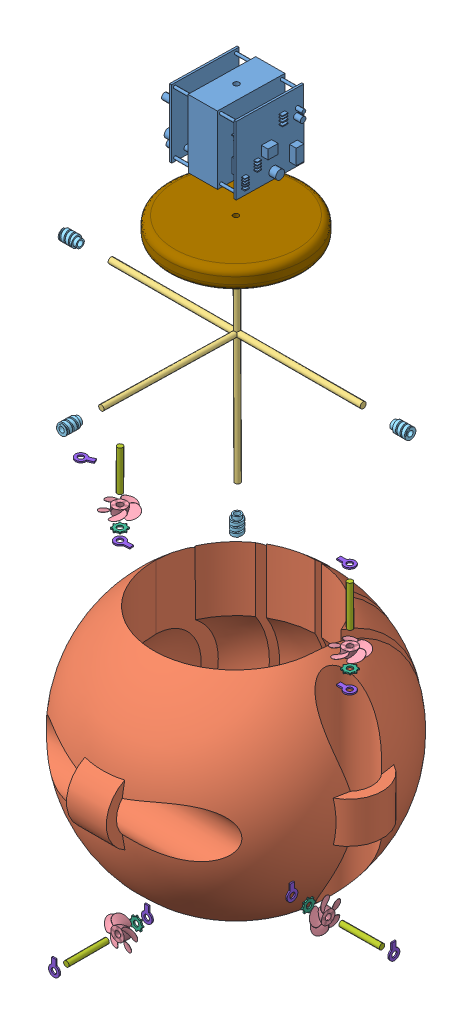
SolidWorks assembly Ensamblaje1, configuration Predeterminado. Lengths in mm.
Overall size (669.49 1060.34 478.47).
28 component instances, 9 part files, 25 mates.
Components (placement in the parent):
- Pieza2-1: Pieza2 [Predeterminado] at (64.4736 1068.7405 131.3597) x (-0.008319 0.010077 0.999915) z (0.999867 0.014123 0.008176) size (100 100 125)
- esfera-1: esfera [Predeterminado] at (14.9319 234.6332 182.7818) x (0.014039 -0.999849 0.010193) z (0.012601 -0.010017 -0.99987) size (380 440 420)
- Ejes 1-1: Ejes 1 [Predeterminado] at (15.2274 748.0482 181.1453) x (0.014039 -0.999849 0.010193) z (-0.012072 0.010024 0.999877) size (290 380 204.4)
- Pieza5-1: Pieza5 [Predeterminado] at (312.8476 234.1846 352.8025) x (0.012182 0.006562 -0.999904) z (0.999904 -0.006643 0.012138) size (49.17 48.96 11.21)
- worm-1: worm [Predeterminado] at (11.9066 750.0271 419.0533) x (0.999927 0.000076 0.012071) z (-0.012072 0.010024 0.999877) size (16 16.41 26.33)
- gear-1: gear [Predeterminado] at (292.0836 234.6768 352.8856) x (0.013028 0.747503 -0.66413) z (0.999904 -0.006643 0.012139) size (19.79 19.79 2)
- Pieza5-2: Pieza5 [Predeterminado] at (-159.673 428.682 180.6096) x (0.999877 0.013966 -0.007207) z (-0.014039 0.999849 -0.010193) size (49.17 48.96 11.21)
- Pieza5-3: Pieza5 [Predeterminado] at (187.121 432.1677 185.2367) x (0.999805 0.013896 -0.014039) z (0.01404 -0.999849 0.010193) size (49.17 48.96 11.21)
- Pieza5-4: Pieza5 [Predeterminado] at (18.1438 63.949 351.8489) x (0.999921 0.000063 0.0126) z (-0.0126 0.010017 0.99987) size (49.17 48.96 11.21)
- gear-2: gear [Predeterminado] at (18.0913 63.9502 332.5107) x (0.999921 0.000063 0.012601) z (-0.012601 0.010017 0.99987) size (19.79 19.79 2)
- gear-3: gear [Predeterminado] at (-159.8331 409.303 180.667) x (0.999805 0.013896 -0.014039) z (0.014039 -0.999849 0.010193) size (19.79 19.79 2)
- gear-4: gear [Predeterminado] at (187.3379 403.5007 185.2315) x (0.999805 0.013896 -0.014039) z (0.014039 -0.999849 0.010193) size (19.79 19.79 2)
- worm-2: worm [Predeterminado] at (257.7732 751.0133 185.3814) x (0.012127 -0.013991 -0.999829) z (0.999829 0.014161 0.011929) size (16 16.41 26.33)
- worm-4: worm [Predeterminado] at (-226.4215 743.3212 178.1967) x (-0.011955 0.001778 0.999927) z (-0.999829 -0.014161 -0.011929) size (16 16.41 26.33)
- worm-5: worm [Predeterminado] at (17.508 512.2725 183.4297) x (-0.848002 -0.017308 -0.52971) z (0.014039 -0.999849 0.010193) size (16 16.41 26.33)
- mini eje-1: mini eje [Predeterminado] at (186.8252 515.3247 184.8611) x (0.09265 -0.00885 -0.995659) z (0.014039 -0.999849 0.010193) size (8 8 60)
- sujeta mini eje-1: sujeta mini eje [Predeterminado] at (187.0855 376.3184 185.3627) x (0.046449 0.010836 0.998862) z (0.014039 -0.999849 0.010193) size (16 24.44 2)
- sujeta mini eje-2: sujeta mini eje [Predeterminado] at (187.0926 538.5053 185.3401) x (0.018929 0.010458 0.999766) z (0.014039 -0.999849 0.010193) size (16 24.44 2)
- sujeta mini eje-3: sujeta mini eje [Predeterminado] at (-159.7165 392.7178 180.7233) x (-0.078161 -0.001677 -0.996939) z (-0.002934 -0.999994 0.001912) size (16 24.44 2)
- mini eje-2: mini eje [Predeterminado] at (-159.9498 454.3157 180.6323) x (0.901566 -0.001818 0.432639) z (0.002934 0.999994 -0.001912) size (8 8 60)
- sujeta mini eje-4: sujeta mini eje [Predeterminado] at (-159.4225 527.599 239.3124) x (0.383182 0.000642 0.923673) z (0.002934 0.999994 -0.001912) size (16 24.44 2)
- mini eje-3: mini eje [Predeterminado] at (18.0004 63.9304 378.3833) size (8 8 60)
- sujeta mini eje-5: sujeta mini eje [Predeterminado] at (18.1274 63.8987 316.8002) size (16 24.44 2)
- sujeta mini eje-6: sujeta mini eje [Predeterminado] at (18.0004 64.0029 454.9079) size (16 24.44 2)
- bateria-1: bateria [Predeterminado] at (14.3008 899.3118 182.0033) x (0.300394 -0.005506 -0.953799) z (0.014039 -0.999849 0.010193) size (200 200 30)
- mini eje-4: mini eje [Predeterminado] at (342.2084 235.1864 352.7964) x (-0.004864 -0.442554 -0.896729) z (0.999976 0.002338 -0.006578) size (8 8 60)
- sujeta mini eje-7: sujeta mini eje [Predeterminado] at (267.6364 235.4041 353.1403) x (-0.006596 0.007693 -0.999949) z (0.999976 0.002338 -0.006578) size (16 24.44 2)
- sujeta mini eje-8: sujeta mini eje [Predeterminado] at (419.4682 235.2957 353.0596) x (-0.006643 0.02898 -0.999558) z (0.999976 0.002338 -0.006578) size (16 24.44 2)
Mates (geometry in assembly coordinates):
- Paralelo1: parallel aligned: cylinder of Pieza2-1 through (14.0644 1068.5383 180.9467) axis (0.014039 -0.999849 0.010193) radius 4; cylinder of Ejes 1-1 through (13.8235 848.0331 180.126) axis (0.014039 -0.999849 0.010193) radius 4
- Paralelo2: parallel anti-aligned: cylinder of esfera-1 through (11.0992 507.5921 179.999) axis (0.014039 -0.999849 0.010193) radius 120; cylinder of Ejes 1-1 through (17.8949 558.0768 183.0821) axis (-0.014039 0.999849 -0.010193) radius 4
- Paralelo3: parallel anti-aligned: cylinder of esfera-1 through (11.0992 507.5921 179.999) axis (0.014039 -0.999849 0.010193) radius 120; cylinder of Ejes 1-1 through (17.8949 558.0768 183.0821) axis (-0.014039 0.999849 -0.010193) radius 4
- Paralelo4: parallel aligned: cylinder of Pieza2-1 through (14.0644 1068.5383 180.9467) axis (0.014039 -0.999849 0.010193) radius 4; cylinder of Ejes 1-1 through (13.8235 848.0331 180.126) axis (0.014039 -0.999849 0.010193) radius 4
- Paralelo5: parallel aligned: cylinder of Ejes 1-1 through (12.8131 750.053 381.1207) axis (0.012072 -0.010024 -0.999877) radius 4; cylinder of worm-1 through (11.6651 750.2276 439.0508) axis (0.012072 -0.010024 -0.999877) radius 4
- Paralelo6: parallel aligned: cylinder of Pieza5-1 through (323.4504 234.1141 352.9312) axis (-0.999904 0.006643 -0.012139) radius 4.2654; cylinder of gear-1 through (294.0835 234.6635 352.9099) axis (-0.999904 0.006643 -0.012139) radius 4
- Paralelo7: parallel aligned: cylinder of Pieza5-1 through (323.4504 234.1141 352.9312) axis (-0.999904 0.006643 -0.012139) radius 4.2654; cylinder of gear-1 through (294.0835 234.6635 352.9099) axis (-0.999904 0.006643 -0.012139) radius 4
- Paralelo8: parallel aligned: cylinder of esfera-1 through (-157.8457 432.1949 178.6252) axis (0.014039 -0.999849 0.010193) radius 35; cylinder of Pieza5-2 through (-159.8219 439.2843 180.5015) axis (0.014039 -0.999849 0.010193) radius 4.2654
- Paralelo9: parallel anti-aligned: cylinder of esfera-1 through (182.0938 437.0113 182.861) axis (0.014039 -0.999849 0.010193) radius 35; cylinder of Pieza5-3 through (187.2699 421.5654 185.3448) axis (-0.014039 0.999849 -0.010193) radius 4.2654
- Paralelo10: parallel aligned: cylinder of esfera-1 through (14.7985 66.6622 384.4888) axis (0.012601 -0.010017 -0.99987) radius 35; cylinder of Pieza5-4 through (18.0102 64.0552 362.4514) axis (0.012601 -0.010017 -0.99987) radius 4.2654
- Paralelo11: parallel aligned: cylinder of esfera-1 through (14.7985 66.6622 384.4888) axis (0.012601 -0.010017 -0.99987) radius 35; cylinder of gear-2 through (18.0661 63.9702 334.5104) axis (0.012601 -0.010017 -0.99987) radius 4
- Paralelo12: parallel anti-aligned: cylinder of esfera-1 through (-157.8457 432.1949 178.6252) axis (0.014039 -0.999849 0.010193) radius 35; cylinder of gear-3 through (-159.805 407.3033 180.6874) axis (-0.014039 0.999849 -0.010193) radius 4
- Paralelo13: parallel anti-aligned: cylinder of esfera-1 through (182.0938 437.0113 182.861) axis (0.014039 -0.999849 0.010193) radius 35; cylinder of gear-4 through (187.366 401.501 185.2519) axis (-0.014039 0.999849 -0.010193) radius 4
- Paralelo14: parallel aligned: cylinder of Ejes 1-1 through (205.1948 750.7387 183.4118) axis (-0.999829 -0.014161 -0.011929) radius 4.4; cylinder of worm-2 through (277.7697 751.2965 185.62) axis (-0.999829 -0.014161 -0.011929) radius 4
- Paralelo16: parallel anti-aligned: cylinder of Ejes 1-1 through (205.1948 750.7387 183.4118) axis (-0.999829 -0.014161 -0.011929) radius 4.4; cylinder of worm-4 through (-246.4181 743.038 177.9582) axis (0.999829 0.014161 0.011929) radius 4
- Paralelo17: parallel aligned: cylinder of Pieza2-1 through (14.0644 1068.5383 180.9467) axis (0.014039 -0.999849 0.010193) radius 4; cylinder of Ejes 1-1 through (13.8235 848.0331 180.126) axis (0.014039 -0.999849 0.010193) radius 4
- Paralelo18: parallel aligned: cylinder of Ejes 1-1 through (17.8949 558.0768 183.0821) axis (-0.014039 0.999849 -0.010193) radius 4; cylinder of worm-5 through (17.7888 492.2755 183.6335) axis (-0.014039 0.999849 -0.010193) radius 4
- Paralelo19: parallel anti-aligned: cylinder of esfera-1 through (182.0938 437.0113 182.861) axis (0.014039 -0.999849 0.010193) radius 35; cylinder of mini eje-1 through (187.6675 455.3337 185.4727) axis (-0.014039 0.999849 -0.010193) radius 4
- Paralelo20: parallel aligned: cylinder of mini eje-1 through (187.6675 455.3337 185.4727) axis (-0.014039 0.999849 -0.010193) radius 4; cylinder of sujeta mini eje-1 through (187.1136 374.3187 185.383) axis (-0.014039 0.999849 -0.010193) radius 4
- Paralelo21: parallel aligned: cylinder of mini eje-1 through (187.6675 455.3337 185.4727) axis (-0.014039 0.999849 -0.010193) radius 4; cylinder of sujeta mini eje-2 through (187.1207 536.5056 185.3605) axis (-0.014039 0.999849 -0.010193) radius 4
- Paralelo22: parallel aligned: cylinder of mini eje-2 through (-159.7738 514.3154 180.5176) axis (-0.002934 -0.999994 0.001912) radius 4; cylinder of sujeta mini eje-4 through (-159.4166 529.599 239.3086) axis (-0.002934 -0.999994 0.001912) radius 4
- Paralelo23: parallel anti-aligned: cylinder of sujeta mini eje-3 through (-159.7223 390.7178 180.7272) axis (0.002934 0.999994 -0.001912) radius 4; cylinder of mini eje-2 through (-159.7738 514.3154 180.5176) axis (-0.002934 -0.999994 0.001912) radius 4
- Paralelo24: parallel anti-aligned: cylinder of Ejes 1-1 through (13.8235 848.0331 180.126) axis (0.014039 -0.999849 0.010193) radius 4; cylinder of bateria-1 through (14.722 869.3163 182.3091) axis (-0.014039 0.999849 -0.010193) radius 4
- Paralelo25: parallel aligned: cylinder of mini eje-4 through (402.207 235.3267 352.4017) axis (-0.999976 -0.002338 0.006578) radius 4; cylinder of sujeta mini eje-8 through (421.4682 235.3004 353.0465) axis (-0.999976 -0.002338 0.006578) radius 4
- Paralelo26: parallel aligned: cylinder of mini eje-4 through (402.207 235.3267 352.4017) axis (-0.999976 -0.002338 0.006578) radius 4; cylinder of sujeta mini eje-7 through (269.6364 235.4087 353.1271) axis (-0.999976 -0.002338 0.006578) radius 4
